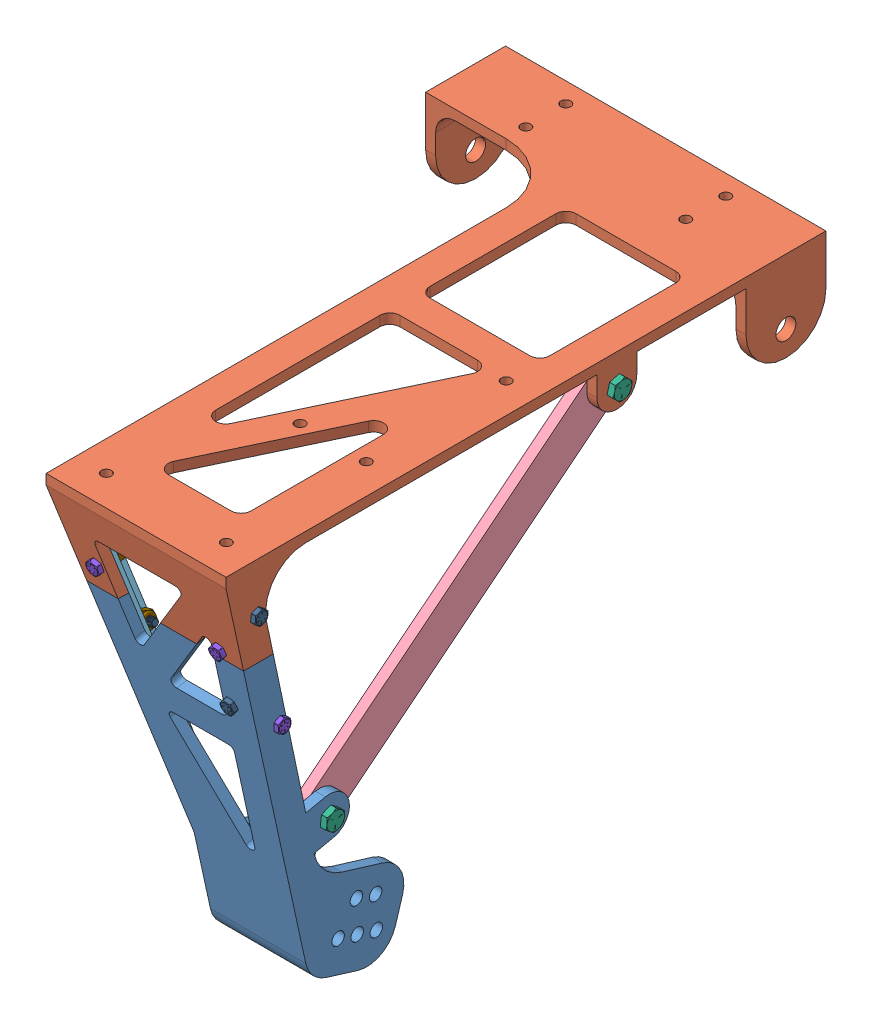
SolidWorks assembly full rear suspention mount, configuration Default. Lengths in mm.
Overall size (207.42 258.99 381).
23 component instances, 10 part files, 44 mates.
Components (placement in the parent):
- Rear Suspension Mount part 2-1: Rear Suspension Mount part 2 [Default] at (-107.4635 247.1448 -61.7021) size (99.8 201.84 101.82)
- Rear Suspension Mount part 1-1: Rear Suspension Mount part 1 [Default] at (-107.4635 247.1448 -61.7021) size (203.45 57.15 381)
- brace-1: brace [Default] at (83.2905 110.3828 232.0615) x (0 0.213829 -0.976871) z (1 0 0) size (12.7 140 13)
- strut-1: strut [Default] at (76.9405 234.4365 20.3068) x (0 -0.624062 0.781375) z (0 0.781375 0.624062) size (258.93 6.35 25.4)
- brace 2-1: brace 2 [Default] at (21.9598 156.434 242.1417) x (0 0.213829 -0.976871) z (0.961833 0.267309 0.058512) size (12.34 98.16 13.85)
- 99894A105_Mil. Spec. Medium-Strength Steel Hex Head Screw-1: 99894A105_Mil. Spec. Medium-Strength Steel Hex Head Screw [99894A105] at (78.9249 234.4448 20.3108) x (-1 0 0) z (0 -0.962937 -0.269725) size (29.84 12.83 11.11)
- 99894A105_Mil. Spec. Medium-Strength Steel Hex Head Screw-2: 99894A105_Mil. Spec. Medium-Strength Steel Hex Head Screw [99894A105] at (78.9249 88.6994 202.7813) x (-1 0 0) z (0 -0.924225 -0.381849) size (29.84 12.83 11.11)
- 95615A120_Medium-Strength Steel Nylon-Insert Locknut-1: 95615A120_Medium-Strength Steel Nylon-Insert Locknut [95615A120] at (72.9718 234.4448 20.3108) x (0 -0.38877 0.921335) z (0 -0.921335 -0.38877) size (11.11 7.94 12.76)
- 95615A120_Medium-Strength Steel Nylon-Insert Locknut-2: 95615A120_Medium-Strength Steel Nylon-Insert Locknut [95615A120] at (72.9718 88.6994 202.7813) x (0 -0.381849 0.924225) z (0 -0.924225 -0.381849) size (11.11 7.94 12.76)
- 92620A417_Zinc Yellow-Chromate Plated Hex Head Screw(1)-1: 92620A417_Zinc Yellow-Chromate Plated Hex Head Screw(1) [92620A417] at (75.5905 201.3393 258.4715) x (0 0.213829 -0.976871) z (0.78277 -0.607918 -0.133068) size (22.62 9.04 7.94)
- 95856A235_Aluminum Nylon-Insert Locknut-1: 95856A235_Aluminum Nylon-Insert Locknut [95856A235] at (75.5905 203.259 249.7017) x (1 0 0) z (0 0.976871 0.213829) size (9.53 6.11 11)
- 92620A417_Zinc Yellow-Chromate Plated Hex Head Screw-3: 92620A417_Zinc Yellow-Chromate Plated Hex Head Screw [92620A417] at (89.6405 222.8078 248.87) x (-1 0 0) z (0 -0.924225 -0.381849) size (22.62 9.04 7.94)
- 95856A235_Aluminum Nylon-Insert Locknut-4: 95856A235_Aluminum Nylon-Insert Locknut [95856A235] at (80.7505 222.8078 248.87) x (0 0.912013 0.410162) z (0 -0.410162 0.912013) size (9.53 6.11 11)
- 92620A417_Zinc Yellow-Chromate Plated Hex Head Screw-4: 92620A417_Zinc Yellow-Chromate Plated Hex Head Screw [92620A417] at (75.5207 167.6373 251.0944) x (0 0.213829 -0.976871) z (0.923874 0.373846 0.081832) size (22.62 9.04 7.94)
- 92620A417_Zinc Yellow-Chromate Plated Hex Head Screw(1)-6: 92620A417_Zinc Yellow-Chromate Plated Hex Head Screw(1) [92620A417] at (89.6405 155.9714 234.2401) x (-1 0 0) z (0 -0.000992 -1) size (22.62 9.04 7.94)
- 95856A235_Aluminum Nylon-Insert Locknut-6: 95856A235_Aluminum Nylon-Insert Locknut [95856A235] at (80.7505 155.9714 234.2401) x (0 -0.178123 0.984008) z (0 -0.984008 -0.178123) size (9.53 6.11 11)
- 95856A235_Aluminum Nylon-Insert Locknut-7: 95856A235_Aluminum Nylon-Insert Locknut [95856A235] at (75.5207 169.5382 242.41) x (-0.484047 0.854803 0.18711) z (-0.875042 -0.472851 -0.103503) size (9.53 6.11 11)
- 92620A417_Zinc Yellow-Chromate Plated Hex Head Screw(1)-7: 92620A417_Zinc Yellow-Chromate Plated Hex Head Screw(1) [92620A417] at (-0.2904 211.1178 260.6119) x (0 0.213829 -0.976871) z (0.976871 0.208884 0.045723) size (22.62 9.04 7.94)
- 95856A235_Aluminum Nylon-Insert Locknut-8: 95856A235_Aluminum Nylon-Insert Locknut [95856A235] at (-0.2904 213.0102 251.9666) x (0.998338 -0.056291 -0.012322) z (0.057624 0.975248 0.213474) size (9.53 6.11 11)
- 92620A417_Zinc Yellow-Chromate Plated Hex Head Screw(1)-8: 92620A417_Zinc Yellow-Chromate Plated Hex Head Screw(1) [92620A417] at (-19.448 224.159 249.3705) x (0.961833 0.267309 0.058512) z (0.251484 -0.947801 0.196033) size (22.62 9.04 7.94)
- 92620A417_Zinc Yellow-Chromate Plated Hex Head Screw-5: 92620A417_Zinc Yellow-Chromate Plated Hex Head Screw [92620A417] at (-3.264 171.3232 237.8052) x (0.961833 0.267309 0.058512) z (-0.107742 0.173398 0.978941) size (22.62 9.04 7.94)
- 95856A235_Aluminum Nylon-Insert Locknut-9: 95856A235_Aluminum Nylon-Insert Locknut [95856A235] at (-9.8769 226.819 249.9528) x (0.24005 -0.9269 0.288502) z (-0.131353 0.263445 0.95569) size (9.53 6.11 11)
- 95856A235_Aluminum Nylon-Insert Locknut-10: 95856A235_Aluminum Nylon-Insert Locknut [95856A235] at (5.5702 173.7784 238.3426) x (0.240076 -0.926953 0.288307) z (-0.131305 0.263256 0.955749) size (9.53 6.11 11)
Mates (geometry in assembly coordinates):
- Coincident1: coincident aligned: plane of Rear Suspension Mount part 2-1 through (-269.1501 247.1448 268.4979) normal (0 -0.213829 0.976871); plane of Rear Suspension Mount part 1-1 through (-269.1501 247.1448 268.4979) normal (0 -0.213829 0.976871)
- Coincident2: coincident anti-aligned: plane of Rear Suspension Mount part 2-1 through (-532.6595 196.3448 -87.1021) normal (0 1 0); plane of Rear Suspension Mount part 1-1 through (394.1865 196.3448 -87.1021) normal (0 -1 0)
- Coincident4: coincident anti-aligned: plane of Rear Suspension Mount part 2-1 through (-269.1501 9.7474 210.0332) normal (0 0.213829 -0.976871); plane of brace-1 through (83.2905 247.1448 261.9976) normal (0 -0.213829 0.976871)
- Coincident5: coincident anti-aligned: plane of Rear Suspension Mount part 2-1 through (83.2905 247.1448 -61.7021) normal (-1 0 0); plane of brace-1 through (83.2905 247.1448 261.9976) normal (1 0 0)
- Coincident9: coincident anti-aligned: plane of Rear Suspension Mount part 2-1 through (-269.1501 9.7474 210.0332) normal (0 0.213829 -0.976871); plane of brace-1 through (83.2905 247.1448 261.9976) normal (0 -0.213829 0.976871)
- Coincident12: coincident aligned: plane of Rear Suspension Mount part 2-1 through (89.6405 253.4948 -61.7021) normal (1 0 0); plane of Rear Suspension Mount part 1-1 through (89.6405 253.4948 -61.7021) normal (1 0 0)
- Coincident13: coincident anti-aligned: circle of Rear Suspension Mount part 2-1; circle of strut-1
- Coincident15: coincident aligned: line of Rear Suspension Mount part 1-1 through (-18.3095 247.1448 261.9976) axis (1 0 0); line of brace-1 through (70.2908 247.1448 261.9976) axis (1 0 0)
- Coincident17: coincident anti-aligned: plane of Rear Suspension Mount part 2-1 through (-269.1501 9.7474 210.0332) normal (0 0.213829 -0.976871); plane of brace 2-1 through (-5.404 250.3926 262.7085) normal (0 -0.213829 0.976871)
- Concentric1: concentric anti-aligned: cylinder of Rear Suspension Mount part 1-1 through (64.2405 234.4448 20.3108) axis (1 0 0) radius 3.175; cylinder of 99894A105_Mil. Spec. Medium-Strength Steel Hex Head Screw-1 through (89.6405 234.4448 20.3108) axis (-1 0 0) radius 3.175
- Coincident19: coincident anti-aligned: plane of Rear Suspension Mount part 1-1 through (89.6405 253.4948 -61.7021) normal (1 0 0); plane of 99894A105_Mil. Spec. Medium-Strength Steel Hex Head Screw-1 through (89.6405 229.9597 15.7231) normal (-1 0 0)
- Concentric2: concentric anti-aligned: cylinder of Rear Suspension Mount part 2-1 through (64.2405 88.6994 202.7813) axis (1 0 0) radius 3.175; cylinder of 99894A105_Mil. Spec. Medium-Strength Steel Hex Head Screw-2 through (89.6405 88.6994 202.7813) axis (-1 0 0) radius 3.175
- Coincident20: coincident anti-aligned: plane of Rear Suspension Mount part 2-1 through (89.6405 253.4948 -61.7021) normal (1 0 0); plane of 99894A105_Mil. Spec. Medium-Strength Steel Hex Head Screw-2 through (89.6405 84.7891 197.6949) normal (-1 0 0)
- Concentric3: concentric aligned: line of 99894A105_Mil. Spec. Medium-Strength Steel Hex Head Screw-1 through (92.0233 234.4448 20.3108) axis (1 0 0); circle of 95615A120_Medium-Strength Steel Nylon-Insert Locknut-1
- Coincident21: coincident anti-aligned: plane of strut-1 through (76.9405 234.4365 20.3068) normal (-1 0 0); plane of 95615A120_Medium-Strength Steel Nylon-Insert Locknut-1 through (76.9405 234.4448 20.3108) normal (1 0 0)
- Concentric4: concentric aligned: line of 99894A105_Mil. Spec. Medium-Strength Steel Hex Head Screw-2 through (92.0233 88.6994 202.7813) axis (1 0 0); circle of 95615A120_Medium-Strength Steel Nylon-Insert Locknut-2
- Coincident22: coincident anti-aligned: plane of strut-1 through (76.9405 234.4365 20.3068) normal (-1 0 0); plane of 95615A120_Medium-Strength Steel Nylon-Insert Locknut-2 through (76.9405 88.6994 202.7813) normal (1 0 0)
- Concentric5: concentric aligned: circle of Rear Suspension Mount part 1-1; circle of 92620A417_Zinc Yellow-Chromate Plated Hex Head Screw-1
- Coincident23: coincident anti-aligned: plane of Rear Suspension Mount part 1-1 through (-269.1501 247.1448 268.4979) normal (0 -0.213829 0.976871); plane of 92620A417_Zinc Yellow-Chromate Plated Hex Head Screw(1)-1 through (78.4424 204.8436 259.2385) normal (0 0.213829 -0.976871)
- Concentric6: concentric aligned: circle of 92620A416_Zinc Yellow-Chromate Plated Hex Head Screw-1; circle of 95856A235_Aluminum Nylon-Insert Locknut-1
- Concentric9: concentric aligned: circle of Rear Suspension Mount part 1-1; circle of 92620A417_Zinc Yellow-Chromate Plated Hex Head Screw-3
- Coincident29: coincident anti-aligned: plane of Rear Suspension Mount part 1-1 through (89.6405 253.4948 -61.7021) normal (1 0 0); plane of 92620A417_Zinc Yellow-Chromate Plated Hex Head Screw-3 through (89.6405 224.5577 244.6345) normal (-1 0 0)
- Concentric10: concentric anti-aligned: circle of 92620A417_Zinc Yellow-Chromate Plated Hex Head Screw-3; circle of 95856A235_Aluminum Nylon-Insert Locknut-4
- Coincident30: coincident anti-aligned: plane of brace-1 through (80.7505 247.6879 259.5163) normal (-1 0 0); plane of 95856A235_Aluminum Nylon-Insert Locknut-4 through (80.7505 221.8477 239.3935) normal (1 0 0)
- Concentric11: concentric anti-aligned: circle of brace-1; circle of 92620A417_Zinc Yellow-Chromate Plated Hex Head Screw(1)-6
- Coincident31: coincident anti-aligned: plane of Rear Suspension Mount part 2-1 through (89.6405 253.4948 -61.7021) normal (1 0 0); plane of 92620A417_Zinc Yellow-Chromate Plated Hex Head Screw(1)-6 through (89.6405 160.5541 234.2355) normal (-1 0 0)
- Concentric12: concentric anti-aligned: cylinder of Rear Suspension Mount part 2-1 through (75.5207 166.8568 254.66) axis (0 0.213829 -0.976871) radius 2.415; circle of 92620A417_Zinc Yellow-Chromate Plated Hex Head Screw-4
- Coincident32: coincident anti-aligned: plane of Rear Suspension Mount part 2-1 through (-269.1501 247.1448 268.4979) normal (0 -0.213829 0.976871); plane of 92620A417_Zinc Yellow-Chromate Plated Hex Head Screw-4 through (73.7669 171.7732 251.9997) normal (0 0.213829 -0.976871)
- Concentric14: concentric anti-aligned: circle of 92620A417_Zinc Yellow-Chromate Plated Hex Head Screw-4; circle of 95856A235_Aluminum Nylon-Insert Locknut-7
- Coincident34: coincident anti-aligned: plane of brace-1 through (70.2908 247.6879 259.5163) normal (0 0.213829 -0.976871); plane of 95856A235_Aluminum Nylon-Insert Locknut-7 through (85.0441 169.3677 242.3727) normal (0 -0.213829 0.976871)
- Concentric15: concentric aligned: circle of 92620A417_Zinc Yellow-Chromate Plated Hex Head Screw(1)-6; circle of 95856A235_Aluminum Nylon-Insert Locknut-6
- Coincident36: coincident anti-aligned: plane of brace-1 through (80.7505 247.6879 259.5163) normal (-1 0 0); plane of 95856A235_Aluminum Nylon-Insert Locknut-6 through (80.7505 164.9367 231.023) normal (1 0 0)
- Coincident37: coincident aligned: plane of Rear Suspension Mount part 1-1 through (6.0464 217.4844 224.8235) normal (0.961833 0.267309 0.058512); plane of brace 2-1 through (-5.404 250.3926 262.7085) normal (0.961833 0.267309 0.058512)
- Concentric16: concentric anti-aligned: circle of Rear Suspension Mount part 1-1; circle of 92620A417_Zinc Yellow-Chromate Plated Hex Head Screw(1)-7
- Coincident38: coincident anti-aligned: plane of Rear Suspension Mount part 1-1 through (-269.1501 247.1448 268.4979) normal (0 -0.213829 0.976871); plane of 92620A417_Zinc Yellow-Chromate Plated Hex Head Screw(1)-7 through (-1.2703 215.491 261.5692) normal (0 0.213829 -0.976871)
- Coincident39: coincident anti-aligned: plane of brace 2-1 through (-5.404 250.9272 260.2663) normal (0 0.213829 -0.976871); plane of 95856A235_Aluminum Nylon-Insert Locknut-8 through (-5.5203 205.2336 250.2644) normal (0 -0.213829 0.976871)
- Concentric19: concentric aligned: circle of 92620A417_Zinc Yellow-Chromate Plated Hex Head Screw(1)-7; circle of 95856A235_Aluminum Nylon-Insert Locknut-8
- Concentric20: concentric anti-aligned: circle of brace 2-1; circle of 92620A417_Zinc Yellow-Chromate Plated Hex Head Screw(1)-8
- Tangent6: tangent: cylinder of Rear Suspension Mount part 1-1 through (-19.4958 224.1478 249.368) axis (0.961833 0.267309 0.058512) radius 2.415; curve of 92620A417_Zinc Yellow-Chromate Plated Hex Head Screw(1)-8
- Concentric21: concentric aligned: circle of brace 2-1; circle of 92620A417_Zinc Yellow-Chromate Plated Hex Head Screw-5
- Coincident41: coincident anti-aligned: line of 92620A417_Zinc Yellow-Chromate Plated Hex Head Screw(1)-8 through (-1.6977 229.0921 250.4503) axis (-0.961833 -0.267309 -0.058512); line of 95856A235_Aluminum Nylon-Insert Locknut-9 through (-10.7534 226.5754 249.8994) axis (0.961833 0.267309 0.058512)
- Coincident42: coincident anti-aligned: plane of brace 2-1 through (-16.3208 247.8933 259.6022) normal (0.961833 0.267309 0.058512); plane of 95856A235_Aluminum Nylon-Insert Locknut-9 through (-9.9366 229.0602 240.6954) normal (-0.961833 -0.267309 -0.058512)
- Concentric22: concentric anti-aligned: circle of 92620A417_Zinc Yellow-Chromate Plated Hex Head Screw-5; circle of 95856A235_Aluminum Nylon-Insert Locknut-10
- Coincident43: coincident anti-aligned: plane of brace 2-1 through (-16.3208 247.8933 259.6022) normal (0.961833 0.267309 0.058512); plane of 95856A235_Aluminum Nylon-Insert Locknut-10 through (5.51 176.0214 229.0857) normal (-0.961833 -0.267309 -0.058512)
